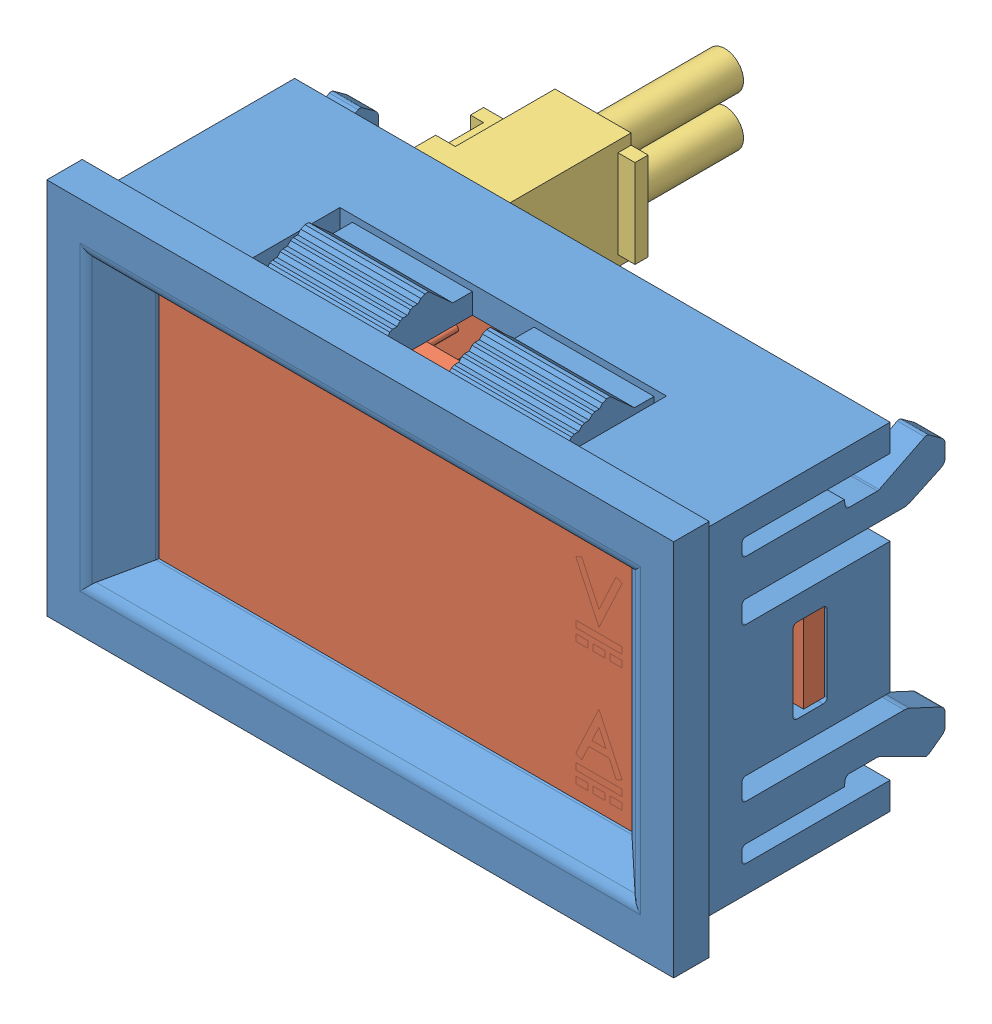
SolidWorks assembly volt-amp, configuration Défaut. Lengths in mm.
Overall size (47.8 28.8 40.1).
4 component instances, 4 part files, 8 mates.
Components (placement in the parent):
- volt-amp_boitier-1: volt-amp_boitier [Défaut] at origin size (47.8 28.8 21.9)
- volt-amp_pcb-1: volt-amp_pcb [Défaut] at origin size (45 21.5 21.1)
- volt-amp_f2p-1: volt-amp_f2p [Défaut] at (-13.6 5.5 -13.8) x (0 1 0) z (0 0 1) size (8.35 11.05 23.6)
- volt-amp_f3p-1: volt-amp_f3p [Défaut] at (-15.5 -6.95 -11.5) size (9.83 5.73 18.1)
Mates (geometry in assembly coordinates):
- Coïncidente1: coordinate: point of ?
- Coïncidente2: coordinate: unknown of ?
- Coïncidente3: coincident: line of volt-amp_pcb-1 through (-8.4 5.5 -13.8) axis (-1 0 0); plane of volt-amp_f2p-1
- Coïncidente4: coincident anti-aligned: plane of volt-amp_pcb-1 through (0 0 -13.8) normal (0 0 -1); plane of volt-amp_f2p-1 through (-13.6 5.5 -13.8) normal (0 0 1)
- Coïncidente5: coincident: point of volt-amp_pcb-1; plane of volt-amp_f2p-1
- Coïncidente6: coincident: line of volt-amp_pcb-1 through (-15.5 -4.95 -11.5) axis (0 -1 0); plane of volt-amp_f3p-1 through (-15.5 -6.95 -11.5) normal (1 0 0)
- Coïncidente7: coincident: point of volt-amp_pcb-1; plane of volt-amp_f3p-1 through (-15.5 -6.95 -11.5) normal (0 1 0)
- Coïncidente9: coincident anti-aligned: plane of volt-amp_pcb-1 through (0 0 -11.5) normal (0 0 -1); plane of volt-amp_f3p-1 through (-15.5 -6.95 -11.5) normal (0 0 1)
